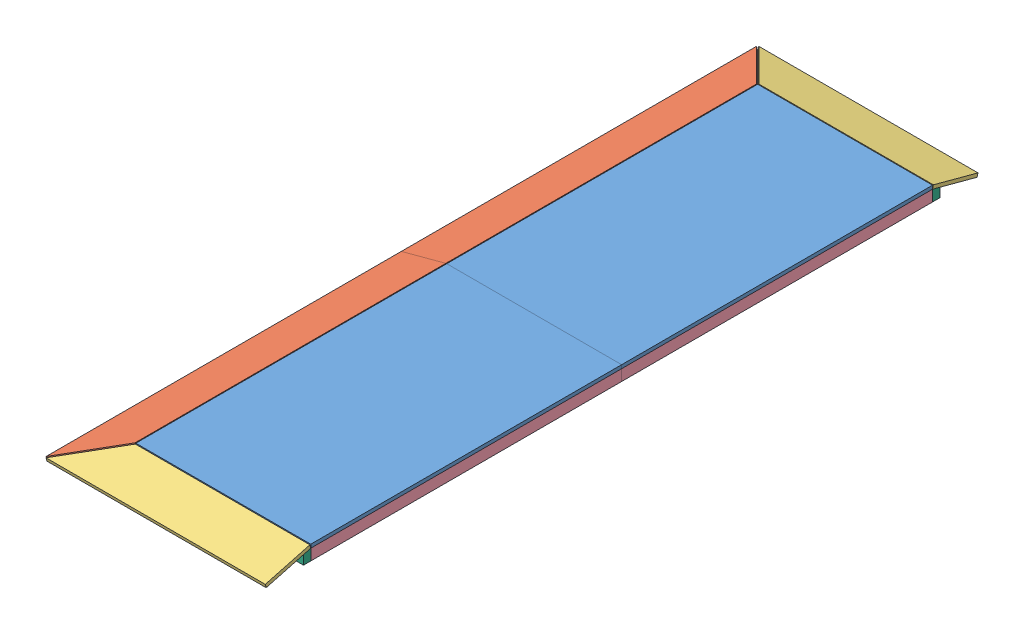
SolidWorks assembly TE-19104, configuration Default. Lengths in mm.
Overall size (1152.2 80.71 3726.81).
22 component instances, 7 part files, 65 mates.
Components (placement in the parent):
- TE-19104-01-5: TE-19104-01 [Default] at (435.5711 76.2 2812.4783) x (0 0 -1) z (0 -1 0) size (1625.6 914.4 18.26)
- TE-19104-01-6: TE-19104-01 [Default] at (435.5711 57.9438 906.0679) x (0 0 1) z (0 1 0) size (1625.6 914.4 18.26)
- TE-19104-03-3: TE-19104-03 [Default] at (-328.4201 -30.0562 2988.6673) x (0 0 1) z (-0.258819 0.965926 0) size (1857.76 241.3 18.26)
- TE-19104-02-1: TE-19104-02 [Default] at (107.0509 8.5369 3669.2619) x (1 0 0) z (0 0.965926 0.258819) size (1146.17 241.3 18.26)
- TE-19104-04-1: TE-19104-04 [Default] at (905.7049 34.983 1859.2731) x (-1 0 0) z (0 0 1) size (38.1 57.94 1625.6)
- TE-19104-04-2: TE-19104-04 [Default] at (8.6951 22.9607 1859.2731) size (38.1 57.94 1625.6)
- TE-19104-04-3: TE-19104-04 [Default] at (8.6951 22.9607 233.6731) size (38.1 57.94 1625.6)
- TE-19104-04-4: TE-19104-04 [Default] at (884.9951 22.9607 233.6731) size (38.1 57.94 1625.6)
- TE-19104-06-1: TE-19104-06 [Default] at (876.3 8.796 3471.0879) x (0 0 1) z (-1 0 0) size (38.1 57.94 838.2)
- TE-19104-06-2: TE-19104-06 [Default] at (38.1 8.796 2395.875) x (0 0 -1) z (1 0 0) size (38.1 57.94 838.2)
- TE-19104-06-3: TE-19104-06 [Default] at (38.1 8.796 2943.0333) x (0 0 -1) z (1 0 0) size (38.1 57.94 838.2)
- TE-19104-06-4: TE-19104-06 [Default] at (38.1 8.796 1312.1417) x (0 0 -1) z (1 0 0) size (38.1 57.94 838.2)
- TE-19104-06-5: TE-19104-06 [Default] at (38.1 8.796 1834.9583) x (0 0 -1) z (1 0 0) size (38.1 57.94 838.2)
- TE-19104-06-6: TE-19104-06 [Default] at (38.1 8.796 247.4583) x (0 0 -1) z (1 0 0) size (38.1 57.94 838.2)
- TE-19104-06-7: TE-19104-06 [Default] at (38.1 8.796 1873.0583) x (0 0 -1) z (1 0 0) size (38.1 57.94 838.2)
- TE-19104-06-8: TE-19104-06 [Default] at (38.1 8.796 770.275) x (0 0 -1) z (1 0 0) size (38.1 57.94 838.2)
- TE-19104-05-1: TE-19104-05 [Default] at (0 22.6542 218.5904) x (0 0 -1) z (1 0 0) size (38.1 57.94 914.4)
- TE-19104-05-2: TE-19104-05 [Default] at (914.4 22.6542 3499.9558) x (0 0 1) z (-1 0 0) size (38.1 57.94 914.4)
- TE-19104-07-1: TE-19104-07 [Default] at (-22.7606 30.5105 3434.0731) x (-1 0 0) z (0 0 -1) size (38.1 57.94 1524)
- TE-19104-07-2: TE-19104-07 [Default] at (-22.7606 30.5105 1808.4731) x (-1 0 0) z (0 0 -1) size (38.1 57.94 1524)
- TE-19104-02-2: TE-19104-02 [Default] at (107.0509 26.1711 44.5592) x (1 0 0) z (0 -0.965926 0.258819) size (1146.17 241.3 18.26)
- TE-19104-03-4: TE-19104-03 [Default] at (-333.1452 -12.422 729.8789) x (0 0 -1) z (0.258819 -0.965926 0) size (1857.76 241.3 18.26)
Mates (geometry in assembly coordinates):
- Coincident57: coincident: plane of TE-19104-01-5 through (914.4 57.9438 3484.8731) normal (1 0 0); plane of TE-19104-02-1 through (914.4 75.5779 3489.5982) normal (1 0 0)
- Coincident65: coincident: plane of TE-19104-01-5 through (435.5711 57.9438 2812.4783) normal (0 -1 0); plane of TE-19104-04-1 through (914.4 57.9438 3484.8731) normal (0 1 0)
- Coincident67: coincident: plane of TE-19104-01-5 through (914.4 57.9438 3484.8731) normal (1 0 0); plane of TE-19104-04-1 through (914.4 0 3484.8731) normal (1 0 0)
- Coincident68: coincident: plane of TE-19104-01-5 through (914.4 57.9438 1859.2731) normal (0 0 -1); plane of TE-19104-04-1 through (905.7049 34.983 1859.2731) normal (0 0 -1)
- Coincident69: coincident: plane of TE-19104-01-5 through (435.5711 57.9438 2812.4783) normal (0 -1 0); plane of TE-19104-04-2 through (0 57.9438 3484.8731) normal (0 1 0)
- Coincident70: coincident: plane of TE-19104-01-5 through (914.4 57.9438 1859.2731) normal (0 0 -1); plane of TE-19104-04-2 through (8.6951 22.9607 1859.2731) normal (0 0 -1)
- Coincident71: coincident: plane of TE-19104-01-5 through (0 57.9438 3484.8731) normal (-1 0 0); plane of TE-19104-04-2 through (0 57.9438 3484.8731) normal (-1 0 0)
- Coincident72: coincident: plane of assembly; plane of assembly; plane of TE-19104-01-6 through (435.5711 57.9438 906.0679) normal (0 -1 0); plane of TE-19104-04-3 through (0 57.9438 1859.2731) normal (0 1 0)
- Coincident73: coincident: plane of assembly; plane of assembly; plane of TE-19104-01-6 through (435.5711 57.9438 906.0679) normal (0 -1 0); plane of TE-19104-04-4 through (876.3 57.9438 1859.2731) normal (0 1 0)
- Coincident74: coincident: plane of assembly; plane of assembly; plane of TE-19104-01-6 through (914.4 76.2 233.6731) normal (1 0 0); plane of TE-19104-04-4 through (914.4 57.9438 1859.2731) normal (1 0 0)
- Coincident75: coincident: plane of assembly; plane of assembly; plane of TE-19104-01-6 through (914.4 76.2 1859.2731) normal (0 0 1); plane of TE-19104-04-3 through (8.6951 22.9607 1859.2731) normal (0 0 1)
- Coincident76: coincident: plane of assembly; plane of assembly; plane of TE-19104-01-6 through (914.4 76.2 233.6731) normal (0 0 -1); plane of TE-19104-04-4 through (884.9951 22.9607 233.6731) normal (0 0 -1)
- Coincident77: coincident: plane of assembly; plane of assembly; plane of TE-19104-01-6 through (0 76.2 233.6731) normal (-1 0 0); plane of TE-19104-04-3 through (0 57.9438 1859.2731) normal (-1 0 0)
- Coincident78: coincident: plane of TE-19104-01-5 through (435.5711 57.9438 2812.4783) normal (0 -1 0); plane of TE-19104-06-1 through (38.1 57.9438 3446.7731) normal (0 1 0)
- Coincident79: coincident: plane of assembly; plane of assembly; plane of TE-19104-04-1 through (905.7049 34.983 3484.8731) normal (0 0 1); plane of TE-19104-06-1 through (38.1 57.9438 3484.8731) normal (0 0 1)
- Coincident80: coincident: plane of assembly; plane of assembly; plane of TE-19104-04-1 through (876.3 0 3484.8731) normal (-1 0 0); plane of TE-19104-06-1 through (876.3 8.796 3471.0879) normal (1 0 0)
- Coincident81: coincident: plane of TE-19104-01-5 through (435.5711 57.9438 2812.4783) normal (0 -1 0); plane of TE-19104-06-7 through (876.3 57.9438 1897.3731) normal (0 1 0)
- Coincident82: coincident: plane of assembly; plane of assembly; plane of TE-19104-04-2 through (38.1 57.9438 3484.8731) normal (1 0 0); plane of TE-19104-06-7 through (38.1 8.796 1873.0583) normal (-1 0 0)
- Coincident83: coincident: line of assembly; plane of assembly; line of TE-19104-04-2 through (38.1 0 1859.2731) axis (0 1 0); plane of TE-19104-06-7 through (876.3 57.9438 1859.2731) normal (0 0 -1)
- Coincident84: coincident: plane of assembly; plane of assembly; plane of TE-19104-01-6 through (435.5711 57.9438 906.0679) normal (0 -1 0); plane of TE-19104-06-6 through (876.3 57.9438 271.7731) normal (0 1 0)
- Coincident85: coincident: plane of assembly; plane of assembly; plane of TE-19104-04-3 through (8.6951 22.9607 233.6731) normal (0 0 -1); plane of TE-19104-06-6 through (876.3 57.9438 233.6731) normal (0 0 -1)
- Coincident86: coincident: plane of assembly; plane of assembly; plane of TE-19104-04-4 through (876.3 57.9438 1859.2731) normal (-1 0 0); plane of TE-19104-06-6 through (876.3 8.796 247.4583) normal (1 0 0)
- Coincident87: coincident: plane of assembly; plane of assembly; plane of TE-19104-01-6 through (435.5711 57.9438 906.0679) normal (0 -1 0); plane of TE-19104-06-5 through (876.3 57.9438 1859.2731) normal (0 1 0)
- Coincident88: coincident: plane of assembly; plane of assembly; plane of TE-19104-06-5 through (876.3 57.9438 1859.2731) normal (0 0 1); plane of TE-19104-06-7 through (876.3 57.9438 1859.2731) normal (0 0 -1)
- Coincident89: coincident: plane of assembly; plane of assembly; plane of TE-19104-04-4 through (876.3 57.9438 1859.2731) normal (-1 0 0); plane of TE-19104-06-5 through (876.3 8.796 1834.9583) normal (1 0 0)
- Symmetric1: symmetric: plane of assembly; plane of assembly; plane of TE-19104-06-3 through (876.3 57.9438 2929.2481) normal (0 0 -1); plane of TE-19104-06-3 through (876.3 57.9438 2967.3481) normal (0 0 1); plane of assembly
- Coincident90: coincident: plane of TE-19104-01-5 through (435.5711 57.9438 2812.4783) normal (0 -1 0); plane of TE-19104-06-3 through (876.3 57.9438 2967.3481) normal (0 1 0)
- Coincident91: coincident: plane of assembly; plane of assembly; plane of TE-19104-04-1 through (876.3 0 3484.8731) normal (-1 0 0); plane of TE-19104-06-3 through (876.3 8.796 2943.0333) normal (1 0 0)
- Symmetric2: symmetric: plane of assembly; plane of assembly; plane of TE-19104-06-2 through (876.3 57.9438 2382.0898) normal (0 0 -1); plane of TE-19104-06-2 through (876.3 57.9438 2420.1898) normal (0 0 1); plane of assembly
- Coincident92: coincident: plane of assembly; plane of assembly; plane of TE-19104-04-1 through (876.3 0 3484.8731) normal (-1 0 0); plane of TE-19104-06-2 through (876.3 8.796 2395.875) normal (1 0 0)
- Coincident93: coincident: plane of TE-19104-01-5 through (435.5711 57.9438 2812.4783) normal (0 -1 0); plane of TE-19104-06-2 through (876.3 57.9438 2420.1898) normal (0 1 0)
- Symmetric3: symmetric: plane of assembly; plane of assembly; plane of TE-19104-06-8 through (876.3 57.9438 756.4898) normal (0 0 -1); plane of TE-19104-06-8 through (876.3 57.9438 794.5898) normal (0 0 1); plane of assembly
- Symmetric4: symmetric: plane of assembly; plane of assembly; plane of TE-19104-06-4 through (876.3 57.9438 1298.3564) normal (0 0 -1); plane of TE-19104-06-4 through (876.3 57.9438 1336.4564) normal (0 0 1); plane of assembly
- Coincident94: coincident: plane of assembly; plane of assembly; plane of TE-19104-01-6 through (435.5711 57.9438 906.0679) normal (0 -1 0); plane of TE-19104-06-8 through (876.3 57.9438 794.5898) normal (0 1 0)
- Coincident95: coincident: plane of assembly; plane of assembly; plane of TE-19104-01-6 through (435.5711 57.9438 906.0679) normal (0 -1 0); plane of TE-19104-06-4 through (876.3 57.9438 1336.4564) normal (0 1 0)
- Coincident96: coincident: plane of assembly; plane of assembly; plane of TE-19104-04-4 through (876.3 57.9438 1859.2731) normal (-1 0 0); plane of TE-19104-06-8 through (876.3 8.796 770.275) normal (1 0 0)
- Coincident97: coincident: plane of assembly; plane of assembly; plane of TE-19104-04-4 through (876.3 57.9438 1859.2731) normal (-1 0 0); plane of TE-19104-06-4 through (876.3 8.796 1312.1417) normal (1 0 0)
- Coincident98: coincident: plane of assembly; plane of assembly; plane of TE-19104-04-4 through (914.4 57.9438 1859.2731) normal (1 0 0); plane of TE-19104-05-1 through (914.4 22.6542 218.5904) normal (1 0 0)
- Coincident99: coincident: plane of assembly; plane of assembly; plane of TE-19104-06-6 through (876.3 57.9438 233.6731) normal (0 0 -1); plane of TE-19104-05-1 through (914.4 57.9438 233.6731) normal (0 0 1)
- Coincident100: coincident: plane of assembly; plane of assembly; plane of TE-19104-04-4 through (876.3 0 1859.2731) normal (0 -1 0); plane of TE-19104-05-1 through (914.4 0 233.6731) normal (0 -1 0)
- Coincident101: coincident: plane of assembly; plane of assembly; plane of TE-19104-04-1 through (914.4 0 3484.8731) normal (1 0 0); plane of TE-19104-05-2 through (914.4 22.6542 3499.9558) normal (1 0 0)
- Coincident102: coincident: plane of assembly; plane of assembly; plane of TE-19104-06-1 through (38.1 57.9438 3484.8731) normal (0 0 1); plane of TE-19104-05-2 through (0 57.9438 3484.8731) normal (0 0 -1)
- Coincident105: coincident: plane of assembly; plane of assembly; plane of TE-19104-06-1 through (38.1 0 3446.7731) normal (0 -1 0); plane of TE-19104-05-2 through (0 0 3484.8731) normal (0 -1 0)
- Coincident106: coincident: plane of assembly; plane of assembly; plane of TE-19104-04-2 through (0 57.9438 3484.8731) normal (-1 0 0); plane of TE-19104-07-1 through (0 57.9438 1910.0731) normal (1 0 0)
- Coincident109: coincident: plane of assembly; plane of assembly; plane of TE-19104-04-2 through (0 0 3484.8731) normal (0 -1 0); plane of TE-19104-07-1 through (0 0 1910.0731) normal (0 -1 0)
- Coincident110: coincident: line of ? through (0 0 3540.9817) axis (1 0 0); plane of ? through (-22.7606 30.5105 3540.9817) normal (0 0 1)
- Coincident112: coincident: plane of ? through (-22.7606 30.5105 2016.9817) normal (0 0 -1); plane of ? through (-22.7606 30.5105 2016.9817) normal (0 0 1)
- Coincident113: coincident: plane of TE-19104-04-3 through (0 57.9438 1859.2731) normal (-1 0 0); plane of ? through (0 57.9438 257.0968) normal (1 0 0)
- Coincident114: coincident: plane of TE-19104-04-3 through (0 0 1859.2731) normal (0 -1 0); plane of ? through (0 0 257.0968) normal (0 -1 0)
- Coincident116: coincident: line of assembly; line of TE-19104-01-6 through (0 76.2 233.6731) axis (0 0 1); plane of assembly
- Coincident117: coincident: plane of assembly through (0 0 0) normal (0 1 0); plane of TE-19104-04-4 through (876.3 0 1859.2731) normal (0 -1 0); plane of assembly
- Distance6: distance = 50.8 mm: plane of assembly; plane of assembly; plane of TE-19104-07-1 through (-22.7606 30.5105 1910.0731) normal (0 0 -1); plane of TE-19104-03-3 through (-4.7251 75.5779 1859.2731) normal (0 0 -1)
- Coincident118: coincident: plane of assembly; plane of assembly; plane of TE-19104-05-1 through (914.4 57.9438 233.6731) normal (0 0.965926 -0.258819); plane of TE-19104-02-2 through (107.0509 8.5369 49.2843) normal (0 -0.965926 0.258819)
- Coincident119: coincident: plane of assembly; plane of assembly; plane of TE-19104-05-1 through (914.4 22.6542 218.5904) normal (1 0 0); plane of TE-19104-02-2 through (914.4 57.9438 233.6731) normal (1 0 0)
- Coincident120: coincident: line of assembly; line of assembly; line of TE-19104-05-1 through (914.4 57.9438 233.6731) axis (-1 0 0); line of TE-19104-02-2 through (914.4 57.9438 233.6731) axis (-1 0 0)
- Coincident121: coincident: plane of ? through (0 57.9438 257.0968) normal (-0.258819 0.965926 0); plane of TE-19104-03-4 through (-328.4201 -30.0562 729.8789) normal (0.258819 -0.965926 0)
- Coincident122: coincident: plane of assembly; plane of assembly; plane of TE-19104-03-3 through (-4.7251 75.5779 1859.2731) normal (0 0 -1); plane of TE-19104-03-4 through (0 57.9438 1859.2731) normal (0 0 1)
- Coincident123: coincident: line of ? through (0 57.9438 257.0968) axis (0 0 1); line of TE-19104-03-4 through (0 57.9438 233.6731) axis (0 0 1)
- Coincident126: coincident: plane of assembly; plane of assembly; plane of TE-19104-03-3 through (-328.4201 -30.0562 2988.6673) normal (0.258819 -0.965926 0); plane of TE-19104-07-1 through (0 57.9438 1910.0731) normal (-0.258819 0.965926 0)
- Coincident127: coincident: line of assembly; line of assembly; line of TE-19104-03-3 through (0 57.9438 3484.8731) axis (0 0 -1); line of TE-19104-07-1 through (0 57.9438 1910.0731) axis (0 0 1)
- Coincident130: coincident: plane of assembly; plane of assembly; plane of TE-19104-02-1 through (107.0509 8.5369 3669.2619) normal (0 -0.965926 -0.258819); plane of TE-19104-05-2 through (0 57.9438 3484.8731) normal (0 0.965926 0.258819)
- Coincident131: coincident: line of assembly; line of assembly; line of TE-19104-02-1 through (914.4 57.9438 3484.8731) axis (-1 0 0); line of TE-19104-05-2 through (0 57.9438 3484.8731) axis (1 0 0)
- Coincident134: coincident: plane of TE-19104-01-5 through (914.4 57.9438 1859.2731) normal (0 0 -1); plane of TE-19104-03-3 through (-4.7251 75.5779 1859.2731) normal (0 0 -1)
- Distance7: distance = 50.8 mm: line of assembly; plane of assembly; line of TE-19104-04-2 through (0 57.9438 1859.2731) axis (0 -1 0); plane of TE-19104-07-1 through (-22.7606 30.5105 1910.0731) normal (0 0 -1)
- Distance8: distance = 50.8 mm: plane of assembly; line of assembly; plane of TE-19104-07-2 through (-22.7606 30.5105 1808.4731) normal (0 0 1); line of TE-19104-04-2 through (0 57.9438 1859.2731) axis (0 -1 0)
